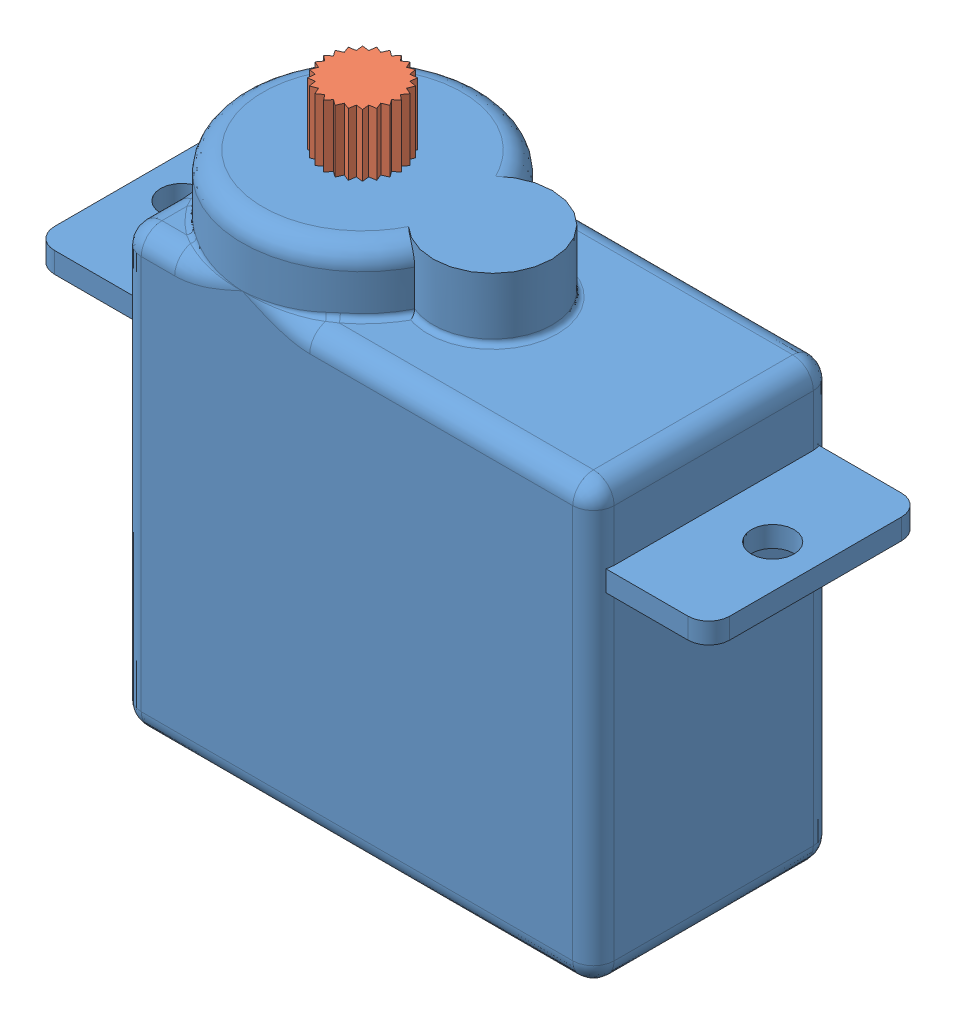
SolidWorks assembly servomoteurhs-55_20181105, configuration Défaut. Lengths in mm.
Overall size (32.54 27 12.17).
2 component instances, 2 part files, 2 mates.
Components (placement in the parent):
- Hi-Tec_HS-55_Bodyvrai-1: Hi-Tec_HS-55_Bodyvrai [Default] at (-48.5327 18.4054 0) size (32.54 24.06 12.17)
- Hi-Tec_HS-55_Shaft-1: Hi-Tec_HS-55_Shaft [Default] at (-48.5327 21.4054 0) size (3.75 3 3.75)
Mates (geometry in assembly coordinates):
- Coïncidente1: coincident: line of Hi-Tec_HS-55_Bodyvrai-1 through (44.567 -48.5327 27.8111) axis (0 0 -1); line of Hi-Tec_HS-55_Shaft-1 through (3.3 -48.5327 21.5554) axis (0 0 -1)
- Coïncidente2: coincident: plane of Hi-Tec_HS-55_Bodyvrai-1 through (-45.3958 18.4054 0) normal (0 1 0); plane of Hi-Tec_HS-55_Shaft-1 through (-48.5327 18.4054 0) normal (0 -1 0)
